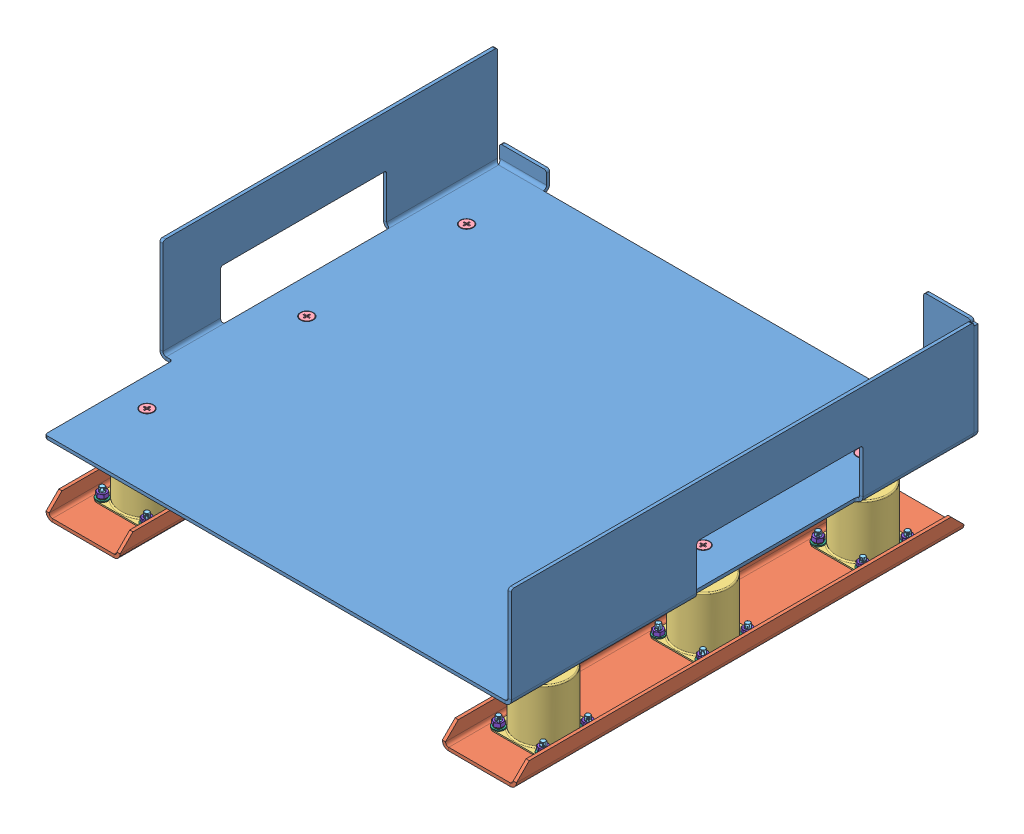
SolidWorks assembly Сборка, configuration По умолчанию. Lengths in mm.
Overall size (375.45 141.9 365.44).
111 component instances, 8 part files, 203 mates.
Components (placement in the parent):
- 1_Полка-1: 1_Полка [По умолчанию<Как обработанный>] at (-182.6691 43.1061 558.1681) size (375.45 80.44 365.44)
- 2_Основание-1: 2_Основание [По умолчанию] at (-150.1691 -18.3939 375.6681) x (0 0 -1) z (1 0 0) size (350 15 58)
- 2_Основание-2: 2_Основание [По умолчанию] at (159.8309 -18.3939 375.6681) x (0 0 1) z (-1 0 0) size (350 15 58)
- 8_Амортизатор-1: 8_Амортизатор [По умолчанию] at (-150.1691 -17.3939 500.6681) size (44 59 44)
- 8_Амортизатор-2: 8_Амортизатор [По умолчанию] at (-150.1691 -17.3939 375.6681) size (44 59 44)
- 8_Амортизатор-3: 8_Амортизатор [По умолчанию] at (159.8309 -17.3939 375.6681) size (44 59 44)
- 8_Амортизатор-4: 8_Амортизатор [По умолчанию] at (159.8309 -17.3939 250.6681) size (44 59 44)
- 8_Амортизатор-5: 8_Амортизатор [По умолчанию] at (159.8309 -17.3939 500.6681) size (44 59 44)
- 8_Амортизатор-6: 8_Амортизатор [По умолчанию] at (-150.1691 -17.3939 250.6681) size (44 59 44)
- 7_Винт_М5-1: 7_Винт_М5 [По умолчанию] at (159.8309 31.2061 250.6681) size (9.3 12.3 9.3)
- 7_Винт_М5-2: 7_Винт_М5 [По умолчанию] at (159.8309 31.2061 500.6681) size (9.3 12.3 9.3)
- 7_Винт_М5-3: 7_Винт_М5 [По умолчанию] at (159.8309 31.2061 375.6681) size (9.3 12.3 9.3)
- 7_Винт_М5-4: 7_Винт_М5 [По умолчанию] at (-150.1691 31.2061 500.6681) size (9.3 12.3 9.3)
- 7_Винт_М5-5: 7_Винт_М5 [По умолчанию] at (-150.1691 31.2061 375.6681) size (9.3 12.3 9.3)
- 7_Винт_М5-6: 7_Винт_М5 [По умолчанию] at (-150.1691 31.2061 250.6681) size (9.3 12.3 9.3)
- 6_Винт_М4-1: 6_Винт_М4 [По умолчанию] at (-132.6691 -9.2939 358.1681) x (1 0 0) z (0 0 -1) size (8.4 12.23 8.4)
- 6_Винт_М4-2: 6_Винт_М4 [По умолчанию] at (-132.6691 -9.2939 393.1681) x (1 0 0) z (0 0 -1) size (8.4 12.23 8.4)
- 6_Винт_М4-3: 6_Винт_М4 [По умолчанию] at (-132.6691 -9.2939 268.1681) x (1 0 0) z (0 0 -1) size (8.4 12.23 8.4)
- 6_Винт_М4-4: 6_Винт_М4 [По умолчанию] at (-132.6691 -9.2939 233.1681) x (1 0 0) z (0 0 -1) size (8.4 12.23 8.4)
- 6_Винт_М4-5: 6_Винт_М4 [По умолчанию] at (-167.6691 -9.2939 268.1681) x (1 0 0) z (0 0 -1) size (8.4 12.23 8.4)
- 6_Винт_М4-6: 6_Винт_М4 [По умолчанию] at (-167.6691 -9.2939 233.1681) x (1 0 0) z (0 0 -1) size (8.4 12.23 8.4)
- 6_Винт_М4-7: 6_Винт_М4 [По умолчанию] at (-167.6691 -9.2939 358.1681) x (1 0 0) z (0 0 -1) size (8.4 12.23 8.4)
- 6_Винт_М4-8: 6_Винт_М4 [По умолчанию] at (-167.6691 -9.2939 393.1681) x (1 0 0) z (0 0 -1) size (8.4 12.23 8.4)
- 6_Винт_М4-9: 6_Винт_М4 [По умолчанию] at (-132.6691 -9.2939 483.1681) x (1 0 0) z (0 0 -1) size (8.4 12.23 8.4)
- 6_Винт_М4-10: 6_Винт_М4 [По умолчанию] at (-167.6691 -9.2939 483.1681) x (1 0 0) z (0 0 -1) size (8.4 12.23 8.4)
- 6_Винт_М4-11: 6_Винт_М4 [По умолчанию] at (-132.6691 -9.2939 518.1681) x (1 0 0) z (0 0 -1) size (8.4 12.23 8.4)
- 6_Винт_М4-12: 6_Винт_М4 [По умолчанию] at (-167.6691 -9.2939 518.1681) x (1 0 0) z (0 0 -1) size (8.4 12.23 8.4)
- 6_Винт_М4-13: 6_Винт_М4 [По умолчанию] at (142.3309 -9.2939 393.1681) x (1 0 0) z (0 0 -1) size (8.4 12.23 8.4)
- 6_Винт_М4-14: 6_Винт_М4 [По умолчанию] at (177.3309 -9.2939 393.1681) x (1 0 0) z (0 0 -1) size (8.4 12.23 8.4)
- 6_Винт_М4-15: 6_Винт_М4 [По умолчанию] at (142.3309 -9.2939 358.1681) x (1 0 0) z (0 0 -1) size (8.4 12.23 8.4)
- 6_Винт_М4-16: 6_Винт_М4 [По умолчанию] at (177.3309 -9.2939 358.1681) x (1 0 0) z (0 0 -1) size (8.4 12.23 8.4)
- 6_Винт_М4-17: 6_Винт_М4 [По умолчанию] at (142.3309 -9.2939 268.1681) x (1 0 0) z (0 0 -1) size (8.4 12.23 8.4)
- 6_Винт_М4-18: 6_Винт_М4 [По умолчанию] at (177.3309 -9.2939 233.1681) x (1 0 0) z (0 0 -1) size (8.4 12.23 8.4)
- 6_Винт_М4-19: 6_Винт_М4 [По умолчанию] at (142.3309 -9.2939 233.1681) x (1 0 0) z (0 0 -1) size (8.4 12.23 8.4)
- 6_Винт_М4-20: 6_Винт_М4 [По умолчанию] at (177.3309 -9.2939 268.1681) x (1 0 0) z (0 0 -1) size (8.4 12.23 8.4)
- 6_Винт_М4-21: 6_Винт_М4 [По умолчанию] at (142.3309 -9.2939 483.1681) x (1 0 0) z (0 0 -1) size (8.4 12.23 8.4)
- 6_Винт_М4-22: 6_Винт_М4 [По умолчанию] at (142.3309 -9.2939 518.1681) x (1 0 0) z (0 0 -1) size (8.4 12.23 8.4)
- 6_Винт_М4-23: 6_Винт_М4 [По умолчанию] at (177.3309 -9.2939 518.1681) x (1 0 0) z (0 0 -1) size (8.4 12.23 8.4)
- 6_Винт_М4-24: 6_Винт_М4 [По умолчанию] at (177.3309 -9.2939 483.1681) x (1 0 0) z (0 0 -1) size (8.4 12.23 8.4)
- 5_Шайба_А4-1: 5_Шайба_А4 [По умолчанию] at (-167.6691 -17.3939 483.1681) size (9 0.8 9)
- 5_Шайба_А4-2: 5_Шайба_А4 [По умолчанию] at (-167.6691 -17.3939 518.1681) size (9 0.8 9)
- 5_Шайба_А4-3: 5_Шайба_А4 [По умолчанию] at (-132.6691 -17.3939 483.1681) size (9 0.8 9)
- 5_Шайба_А4-4: 5_Шайба_А4 [По умолчанию] at (-132.6691 -17.3939 518.1681) size (9 0.8 9)
- 5_Шайба_А4-5: 5_Шайба_А4 [По умолчанию] at (-132.6691 -17.3939 358.1681) size (9 0.8 9)
- 5_Шайба_А4-6: 5_Шайба_А4 [По умолчанию] at (-167.6691 -17.3939 358.1681) x (0.667265 0 0.74482) z (-0.74482 0 0.667265) size (9 0.8 9)
- 5_Шайба_А4-7: 5_Шайба_А4 [По умолчанию] at (-132.6691 -17.3939 393.1681) size (9 0.8 9)
- 5_Шайба_А4-8: 5_Шайба_А4 [По умолчанию] at (-167.6691 -17.3939 393.1681) x (0.975059 0 0.221947) z (-0.221947 0 0.975059) size (9 0.8 9)
- 5_Шайба_А4-9: 5_Шайба_А4 [По умолчанию] at (-167.6691 -17.3939 268.1681) size (9 0.8 9)
- 5_Шайба_А4-10: 5_Шайба_А4 [По умолчанию] at (-132.6691 -17.3939 268.1681) size (9 0.8 9)
- 5_Шайба_А4-11: 5_Шайба_А4 [По умолчанию] at (-167.6691 -17.3939 233.1681) size (9 0.8 9)
- 5_Шайба_А4-12: 5_Шайба_А4 [По умолчанию] at (-132.6691 -17.3939 233.1681) size (9 0.8 9)
- 5_Шайба_А4-13: 5_Шайба_А4 [По умолчанию] at (142.3309 -17.3939 518.1681) size (9 0.8 9)
- 5_Шайба_А4-14: 5_Шайба_А4 [По умолчанию] at (142.3309 -17.3939 483.1681) size (9 0.8 9)
- 5_Шайба_А4-15: 5_Шайба_А4 [По умолчанию] at (177.3309 -17.3939 483.1681) size (9 0.8 9)
- 5_Шайба_А4-16: 5_Шайба_А4 [По умолчанию] at (177.3309 -17.3939 518.1681) size (9 0.8 9)
- 5_Шайба_А4-17: 5_Шайба_А4 [По умолчанию] at (142.3309 -17.3939 358.1681) size (9 0.8 9)
- 5_Шайба_А4-18: 5_Шайба_А4 [По умолчанию] at (177.3309 -17.3939 393.1681) size (9 0.8 9)
- 5_Шайба_А4-19: 5_Шайба_А4 [По умолчанию] at (142.3309 -17.3939 393.1681) size (9 0.8 9)
- 5_Шайба_А4-20: 5_Шайба_А4 [По умолчанию] at (177.3309 -17.3939 358.1681) size (9 0.8 9)
- 5_Шайба_А4-21: 5_Шайба_А4 [По умолчанию] at (142.3309 -17.3939 268.1681) size (9 0.8 9)
- 5_Шайба_А4-22: 5_Шайба_А4 [По умолчанию] at (142.3309 -17.3939 233.1681) size (9 0.8 9)
- 5_Шайба_А4-23: 5_Шайба_А4 [По умолчанию] at (177.3309 -17.3939 233.1681) size (9 0.8 9)
- 5_Шайба_А4-24: 5_Шайба_А4 [По умолчанию] at (177.3309 -17.3939 268.1681) size (9 0.8 9)
- 4_Шайба-1: 4_Шайба [По умолчанию] at (-132.6691 -16.5939 518.1681) x (-0.950092 0 -0.311971) z (0.311971 0 -0.950092) size (6.5 0.8 6.5)
- 4_Шайба-2: 4_Шайба [По умолчанию] at (-167.6691 -16.5939 518.1681) x (-0.964104 0 -0.265525) z (0.265525 0 -0.964104) size (6.5 0.8 6.5)
- 4_Шайба-3: 4_Шайба [По умолчанию] at (-167.6691 -16.5939 483.1681) x (-0.900004 0 -0.435881) z (0.435881 0 -0.900004) size (6.5 0.8 6.5)
- 4_Шайба-4: 4_Шайба [По умолчанию] at (-132.6691 -16.5939 483.1681) x (0.833959 0 0.551827) z (-0.551827 0 0.833959) size (6.5 0.8 6.5)
- 4_Шайба-5: 4_Шайба [По умолчанию] at (-167.6691 -16.5939 358.1681) x (0.466083 0 -0.884741) z (0.884741 0 0.466083) size (6.5 0.8 6.5)
- 4_Шайба-6: 4_Шайба [По умолчанию] at (-132.6691 -16.5939 358.1681) x (0.892908 0 0.450239) z (-0.450239 0 0.892908) size (6.5 0.8 6.5)
- 4_Шайба-7: 4_Шайба [По умолчанию] at (-167.6691 -16.5939 393.1681) x (-0.311106 0 -0.950375) z (0.950375 0 -0.311106) size (6.5 0.8 6.5)
- 4_Шайба-8: 4_Шайба [По умолчанию] at (-132.6691 -16.5939 393.1681) size (6.5 0.8 6.5)
- 4_Шайба-13: 4_Шайба [По умолчанию] at (-132.6691 -16.5939 233.1681) size (6.5 0.8 6.5)
- 4_Шайба-14: 4_Шайба [По умолчанию] at (-167.6691 -16.5939 268.1681) size (6.5 0.8 6.5)
- 4_Шайба-15: 4_Шайба [По умолчанию] at (-132.6691 -16.5939 268.1681) x (0.985052 0 -0.172259) z (0.172259 0 0.985052) size (6.5 0.8 6.5)
- 4_Шайба-16: 4_Шайба [По умолчанию] at (-167.6691 -16.5939 233.1681) size (6.5 0.8 6.5)
- 4_Шайба-17: 4_Шайба [По умолчанию] at (177.3309 -16.5939 518.1681) x (-0.952485 0 -0.304585) z (0.304585 0 -0.952485) size (6.5 0.8 6.5)
- 4_Шайба-19: 4_Шайба [По умолчанию] at (142.3309 -16.5939 518.1681) x (-0.742093 0 -0.670297) z (0.670297 0 -0.742093) size (6.5 0.8 6.5)
- 4_Шайба-20: 4_Шайба [По умолчанию] at (142.3309 -16.5939 483.1681) x (0.157887 0 -0.987457) z (0.987457 0 0.157887) size (6.5 0.8 6.5)
- 4_Шайба-21: 4_Шайба [По умолчанию] at (177.3309 -16.5939 483.1681) x (0.73951 0 0.673145) z (-0.673145 0 0.73951) size (6.5 0.8 6.5)
- 4_Шайба-22: 4_Шайба [По умолчанию] at (177.3309 -16.5939 233.1681) x (0.8131 0 0.582125) z (-0.582125 0 0.8131) size (6.5 0.8 6.5)
- 4_Шайба-23: 4_Шайба [По умолчанию] at (142.3309 -16.5939 233.1681) size (6.5 0.8 6.5)
- 4_Шайба-24: 4_Шайба [По умолчанию] at (142.3309 -16.5939 268.1681) size (6.5 0.8 6.5)
- 4_Шайба-25: 4_Шайба [По умолчанию] at (177.3309 -16.5939 268.1681) x (-0.997954 0 -0.063934) z (0.063934 0 -0.997954) size (6.5 0.8 6.5)
- 4_Шайба-26: 4_Шайба [По умолчанию] at (142.3309 -16.5939 358.1681) size (6.5 0.8 6.5)
- 4_Шайба-27: 4_Шайба [По умолчанию] at (142.3309 -16.5939 393.1681) size (6.5 0.8 6.5)
- 4_Шайба-28: 4_Шайба [По умолчанию] at (177.3309 -16.5939 358.1681) x (0.299403 0 0.954127) z (-0.954127 0 0.299403) size (6.5 0.8 6.5)
- 4_Шайба-29: 4_Шайба [По умолчанию] at (177.3309 -16.5939 393.1681) size (6.5 0.8 6.5)
- 3_Гайка-1: 3_Гайка [По умолчанию] at (142.3309 -15.7939 483.1681) size (6.78 3.14 7.83)
- 3_Гайка-2: 3_Гайка [По умолчанию] at (177.3309 -15.7939 483.1681) size (6.78 3.14 7.83)
- 3_Гайка-3: 3_Гайка [По умолчанию] at (177.3309 -15.7939 518.1681) size (6.78 3.14 7.83)
- 3_Гайка-4: 3_Гайка [По умолчанию] at (142.3309 -15.7939 518.1681) size (6.78 3.14 7.83)
- 3_Гайка-5: 3_Гайка [По умолчанию] at (142.3309 -16.5939 393.1681) size (6.78 3.14 7.83)
- 3_Гайка-6: 3_Гайка [По умолчанию] at (177.3309 -15.7939 393.1681) size (6.78 3.14 7.83)
- 3_Гайка-7: 3_Гайка [По умолчанию] at (177.3309 -15.7939 358.1681) size (6.78 3.14 7.83)
- 3_Гайка-8: 3_Гайка [По умолчанию] at (142.3309 -15.7939 358.1681) size (6.78 3.14 7.83)
- 3_Гайка-9: 3_Гайка [По умолчанию] at (177.3309 -15.7939 268.1681) size (6.78 3.14 7.83)
- 3_Гайка-10: 3_Гайка [По умолчанию] at (142.3309 -15.7939 233.1681) size (6.78 3.14 7.83)
- 3_Гайка-11: 3_Гайка [По умолчанию] at (177.3309 -15.7939 233.1681) size (6.78 3.14 7.83)
- 3_Гайка-12: 3_Гайка [По умолчанию] at (142.3309 -15.7939 268.1681) x (0.892685 0 0.450682) z (-0.450682 0 0.892685) size (6.78 3.14 7.83)
- 3_Гайка-13: 3_Гайка [По умолчанию] at (-167.6691 -15.7939 268.1681) size (6.78 3.14 7.83)
- 3_Гайка-14: 3_Гайка [По умолчанию] at (-167.6691 -15.7939 233.1681) size (6.78 3.14 7.83)
- 3_Гайка-15: 3_Гайка [По умолчанию] at (-132.6691 -15.7939 233.1681) x (0.109606 0 -0.993975) z (0.993975 0 0.109606) size (6.78 3.14 7.83)
- 3_Гайка-16: 3_Гайка [По умолчанию] at (-132.6691 -15.7939 268.1681) size (6.78 3.14 7.83)
- 3_Гайка-17: 3_Гайка [По умолчанию] at (-167.6691 -15.7939 358.1681) size (6.78 3.14 7.83)
- 3_Гайка-18: 3_Гайка [По умолчанию] at (-132.6691 -15.7939 393.1681) size (6.78 3.14 7.83)
- 3_Гайка-19: 3_Гайка [По умолчанию] at (-167.6691 -15.7939 393.1681) size (6.78 3.14 7.83)
- 3_Гайка-20: 3_Гайка [По умолчанию] at (-132.6691 -15.7939 358.1681) size (6.78 3.14 7.83)
- 3_Гайка-21: 3_Гайка [По умолчанию] at (-132.6691 -15.7939 483.1681) size (6.78 3.14 7.83)
- 3_Гайка-22: 3_Гайка [По умолчанию] at (-167.6691 -15.7939 518.1681) size (6.78 3.14 7.83)
- 3_Гайка-23: 3_Гайка [По умолчанию] at (-132.6691 -15.7939 518.1681) size (6.78 3.14 7.83)
- 3_Гайка-24: 3_Гайка [По умолчанию] at (-167.6691 -15.7939 483.1681) size (6.78 3.14 7.83)
Mates (geometry in assembly coordinates):
- Концентричный1: concentric aligned: circle of 1_Полка-1; circle of 8_Амортизатор-6
- Совпадение2: coincident anti-aligned: plane of 1_Полка-1 through (-182.6691 40.6061 558.1681) normal (0 -1 0); plane of 8_Амортизатор-6 through (-150.1691 40.6061 250.6681) normal (0 1 0)
- Совпадение3: coincident aligned: cone of 1_Полка-1 through (-150.1691 40.7561 250.6681) axis (0 -1 0); cone of 7_Винт_М5-6 through (-150.1691 42.6561 250.6681) axis (0 -1 0)
- Концентричный2: concentric aligned: circle of 1_Полка-1; circle of 8_Амортизатор-2
- Совпадение4: coincident anti-aligned: plane of 1_Полка-1 through (-182.6691 40.6061 558.1681) normal (0 -1 0); plane of 8_Амортизатор-2 through (-150.1691 40.6061 375.6681) normal (0 1 0)
- Концентричный3: concentric aligned: circle of 1_Полка-1; circle of 8_Амортизатор-1
- Совпадение5: coincident anti-aligned: plane of 1_Полка-1 through (-182.6691 40.6061 558.1681) normal (0 -1 0); plane of 8_Амортизатор-1 through (-150.1691 40.6061 500.6681) normal (0 1 0)
- Концентричный4: concentric aligned: circle of 1_Полка-1; circle of 8_Амортизатор-4
- Совпадение6: coincident anti-aligned: plane of 1_Полка-1 through (-182.6691 40.6061 558.1681) normal (0 -1 0); plane of 8_Амортизатор-4 through (159.8309 40.6061 250.6681) normal (0 1 0)
- Концентричный5: concentric aligned: circle of 1_Полка-1; circle of 8_Амортизатор-3
- Совпадение7: coincident anti-aligned: plane of 1_Полка-1 through (-182.6691 40.6061 558.1681) normal (0 -1 0); plane of 8_Амортизатор-3 through (159.8309 40.6061 375.6681) normal (0 1 0)
- Концентричный6: concentric aligned: circle of 1_Полка-1; circle of 8_Амортизатор-5
- Совпадение8: coincident anti-aligned: plane of 1_Полка-1 through (-182.6691 40.6061 558.1681) normal (0 -1 0); plane of 8_Амортизатор-5 through (159.8309 40.6061 500.6681) normal (0 1 0)
- Совпадение9: coincident aligned: cone of 1_Полка-1 through (-150.1691 40.7561 375.6681) axis (0 -1 0); cone of 7_Винт_М5-5 through (-150.1691 42.6561 375.6681) axis (0 -1 0)
- Совпадение10: coincident aligned: cone of 1_Полка-1 through (-150.1691 40.7561 500.6681) axis (0 -1 0); cone of 7_Винт_М5-4 through (-150.1691 42.6561 500.6681) axis (0 -1 0)
- Совпадение11: coincident aligned: cone of 1_Полка-1 through (159.8309 40.7561 500.6681) axis (0 -1 0); cone of 7_Винт_М5-2 through (159.8309 42.6561 500.6681) axis (0 -1 0)
- Совпадение12: coincident aligned: cone of 1_Полка-1 through (159.8309 40.7561 375.6681) axis (0 -1 0); cone of 7_Винт_М5-3 through (159.8309 42.6561 375.6681) axis (0 -1 0)
- Совпадение14: coincident aligned: cone of 1_Полка-1 through (159.8309 40.7561 250.6681) axis (0 -1 0); cone of 7_Винт_М5-1 through (159.8309 42.6561 250.6681) axis (0 -1 0)
- Концентричный11: concentric aligned: circle of 2_Основание-1; circle of 8_Амортизатор-6
- Концентричный12: concentric aligned: circle of 2_Основание-1; circle of 8_Амортизатор-6
- Концентричный13: concentric aligned: circle of 2_Основание-1; circle of 8_Амортизатор-2
- Концентричный14: concentric anti-aligned: cylinder of 2_Основание-1; cylinder of 8_Амортизатор-2 through (-132.6691 24.8061 393.1681) axis (0 -1 0) radius 2
- Концентричный15: concentric anti-aligned: circle of 2_Основание-1; cylinder of 8_Амортизатор-1 through (-167.6691 24.8061 483.1681) axis (0 -1 0) radius 2
- Концентричный16: concentric aligned: circle of 2_Основание-1; circle of 8_Амортизатор-1
- Совпадение15: coincident anti-aligned: plane of 2_Основание-1 through (-150.1691 -18.3939 375.6681) normal (0 1 0); plane of 8_Амортизатор-1 through (-150.1691 -18.3939 500.6681) normal (0 -1 0)
- Совпадение16: coincident aligned: cone of 2_Основание-1 through (-167.6691 -20.8939 518.1681) axis (0 1 0); cone of 6_Винт_М4-12 through (-167.6691 -20.7939 518.1681) axis (0 1 0)
- Совпадение17: coincident aligned: cone of 2_Основание-1 through (-132.6691 -20.8939 518.1681) axis (0 1 0); cone of 6_Винт_М4-11 through (-132.6691 -20.7939 518.1681) axis (0 1 0)
- Совпадение18: coincident anti-aligned: cone of 2_Основание-1 through (-167.6691 -20.8939 483.1681) axis (0 1 0); circle of 6_Винт_М4-10
- Совпадение19: coincident anti-aligned: cone of 2_Основание-1 through (-132.6691 -20.8939 483.1681) axis (0 1 0); circle of 6_Винт_М4-9
- Совпадение20: coincident aligned: cone of 2_Основание-1 through (-167.6691 -20.8939 393.1681) axis (0 1 0); cone of 6_Винт_М4-8 through (-167.6691 -20.7939 393.1681) axis (0 1 0)
- Совпадение21: coincident aligned: cone of 2_Основание-1 through (-132.6691 -20.8939 358.1681) axis (0 1 0); cone of 6_Винт_М4-1 through (-132.6691 -20.7939 358.1681) axis (0 1 0)
- Совпадение22: coincident aligned: cone of 2_Основание-1 through (-167.6691 -20.8939 358.1681) axis (0 1 0); cone of 6_Винт_М4-7 through (-167.6691 -20.7939 358.1681) axis (0 1 0)
- Совпадение23: coincident aligned: cone of 2_Основание-1 through (-132.6691 -20.8939 393.1681) axis (0 1 0); cone of 6_Винт_М4-2 through (-132.6691 -20.7939 393.1681) axis (0 1 0)
- Совпадение24: coincident aligned: cone of 2_Основание-1 through (-167.6691 -20.8939 268.1681) axis (0 1 0); cone of 6_Винт_М4-5 through (-167.6691 -20.7939 268.1681) axis (0 1 0)
- Совпадение25: coincident aligned: cone of 2_Основание-1 through (-167.6691 -20.8939 233.1681) axis (0 1 0); cone of 6_Винт_М4-6 through (-167.6691 -20.7939 233.1681) axis (0 1 0)
- Совпадение26: coincident aligned: cone of 2_Основание-1 through (-132.6691 -20.8939 233.1681) axis (0 1 0); cone of 6_Винт_М4-4 through (-132.6691 -20.7939 233.1681) axis (0 1 0)
- Совпадение27: coincident aligned: cone of 2_Основание-1 through (-132.6691 -20.8939 268.1681) axis (0 1 0); cone of 6_Винт_М4-3 through (-132.6691 -20.7939 268.1681) axis (0 1 0)
- Концентричный17: concentric anti-aligned: circle of 2_Основание-2; cylinder of 8_Амортизатор-5 through (142.3309 24.8061 483.1681) axis (0 -1 0) radius 2
- Концентричный18: concentric anti-aligned: circle of 2_Основание-2; cylinder of 8_Амортизатор-5 through (177.3309 24.8061 518.1681) axis (0 -1 0) radius 2
- Концентричный19: concentric anti-aligned: circle of 2_Основание-2; cylinder of 8_Амортизатор-3 through (142.3309 24.8061 393.1681) axis (0 -1 0) radius 2
- Концентричный20: concentric aligned: circle of 2_Основание-2; circle of 8_Амортизатор-3
- Концентричный21: concentric anti-aligned: circle of 2_Основание-2; cylinder of 8_Амортизатор-4 through (142.3309 24.8061 268.1681) axis (0 -1 0) radius 2
- Концентричный22: concentric anti-aligned: circle of 2_Основание-2; cylinder of 8_Амортизатор-4 through (177.3309 24.8061 233.1681) axis (0 -1 0) radius 2
- Совпадение28: coincident anti-aligned: plane of 2_Основание-2 through (159.8309 -18.3939 375.6681) normal (0 1 0); plane of 8_Амортизатор-5 through (159.8309 -18.3939 500.6681) normal (0 -1 0)
- Совпадение29: coincident aligned: cone of 2_Основание-2 through (142.3309 -20.8939 518.1681) axis (0 1 0); cone of 6_Винт_М4-22 through (142.3309 -20.7939 518.1681) axis (0 1 0)
- Совпадение30: coincident aligned: cone of 2_Основание-2 through (177.3309 -20.8939 518.1681) axis (0 1 0); cone of 6_Винт_М4-23 through (177.3309 -20.7939 518.1681) axis (0 1 0)
- Совпадение31: coincident aligned: cone of 2_Основание-2 through (142.3309 -20.8939 483.1681) axis (0 1 0); cone of 6_Винт_М4-21 through (142.3309 -20.7939 483.1681) axis (0 1 0)
- Совпадение32: coincident aligned: cone of 2_Основание-2 through (177.3309 -20.8939 483.1681) axis (0 1 0); cone of 6_Винт_М4-24 through (177.3309 -20.7939 483.1681) axis (0 1 0)
- Совпадение33: coincident aligned: cone of 2_Основание-2 through (142.3309 -20.8939 393.1681) axis (0 1 0); cone of 6_Винт_М4-13 through (142.3309 -20.7939 393.1681) axis (0 1 0)
- Совпадение34: coincident aligned: cone of 2_Основание-2 through (177.3309 -20.8939 393.1681) axis (0 1 0); cone of 6_Винт_М4-14 through (177.3309 -20.7939 393.1681) axis (0 1 0)
- Совпадение35: coincident aligned: cone of 2_Основание-2 through (142.3309 -20.8939 358.1681) axis (0 1 0); cone of 6_Винт_М4-15 through (142.3309 -20.7939 358.1681) axis (0 1 0)
- Совпадение36: coincident aligned: cone of 2_Основание-2 through (177.3309 -20.8939 358.1681) axis (0 1 0); cone of 6_Винт_М4-16 through (177.3309 -20.7939 358.1681) axis (0 1 0)
- Совпадение37: coincident aligned: cone of 2_Основание-2 through (142.3309 -20.8939 268.1681) axis (0 1 0); cone of 6_Винт_М4-17 through (142.3309 -20.7939 268.1681) axis (0 1 0)
- Совпадение38: coincident aligned: cone of 2_Основание-2 through (177.3309 -20.8939 233.1681) axis (0 1 0); cone of 6_Винт_М4-18 through (177.3309 -20.7939 233.1681) axis (0 1 0)
- Совпадение39: coincident aligned: cone of 2_Основание-2 through (177.3309 -20.8939 268.1681) axis (0 1 0); cone of 6_Винт_М4-20 through (177.3309 -20.7939 268.1681) axis (0 1 0)
- Совпадение40: coincident aligned: cone of 2_Основание-2 through (142.3309 -20.8939 233.1681) axis (0 1 0); cone of 6_Винт_М4-19 through (142.3309 -20.7939 233.1681) axis (0 1 0)
- Совпадение43: coincident anti-aligned: plane of 8_Амортизатор-1 through (-150.1691 -17.3939 500.6681) normal (0 1 0); plane of 5_Шайба_А4-2 through (-167.6691 -17.3939 518.1681) normal (0 -1 0)
- Концентричный24: concentric aligned: circle of 8_Амортизатор-1; circle of 5_Шайба_А4-2
- Совпадение44: coincident anti-aligned: plane of 8_Амортизатор-1 through (-150.1691 -17.3939 500.6681) normal (0 1 0); plane of 5_Шайба_А4-4 through (-132.6691 -17.3939 518.1681) normal (0 -1 0)
- Концентричный25: concentric aligned: circle of 8_Амортизатор-1; circle of 5_Шайба_А4-4
- Совпадение45: coincident anti-aligned: plane of 8_Амортизатор-1 through (-150.1691 -17.3939 500.6681) normal (0 1 0); plane of 5_Шайба_А4-1 through (-167.6691 -17.3939 483.1681) normal (0 -1 0)
- Концентричный26: concentric aligned: circle of 8_Амортизатор-1; circle of 5_Шайба_А4-1
- Совпадение46: coincident aligned: plane of 8_Амортизатор-1 through (-150.1691 -17.3939 500.6681) normal (0 1 0); circle of 5_Шайба_А4-3
- Концентричный27: concentric aligned: circle of 8_Амортизатор-1; circle of 5_Шайба_А4-3
- Концентричный28: concentric aligned: circle of 8_Амортизатор-2; circle of 5_Шайба_А4-7
- Совпадение47: coincident anti-aligned: plane of 8_Амортизатор-2 through (-150.1691 -17.3939 375.6681) normal (0 1 0); plane of 5_Шайба_А4-7 through (-132.6691 -17.3939 393.1681) normal (0 -1 0)
- Концентричный29: concentric aligned: circle of 8_Амортизатор-2; circle of 5_Шайба_А4-8
- Совпадение49: coincident anti-aligned: plane of 8_Амортизатор-2 through (-150.1691 -17.3939 375.6681) normal (0 1 0); plane of 5_Шайба_А4-8 through (-167.6691 -17.3939 393.1681) normal (0 -1 0)
- Концентричный30: concentric aligned: circle of 8_Амортизатор-2; circle of 5_Шайба_А4-6
- Совпадение51: coincident anti-aligned: plane of 8_Амортизатор-2 through (-150.1691 -17.3939 375.6681) normal (0 1 0); plane of 5_Шайба_А4-6 through (-167.6691 -17.3939 358.1681) normal (0 -1 0)
- Концентричный31: concentric aligned: circle of 8_Амортизатор-2; circle of 5_Шайба_А4-5
- Совпадение54: coincident anti-aligned: plane of 8_Амортизатор-2 through (-150.1691 -17.3939 375.6681) normal (0 1 0); plane of 5_Шайба_А4-5 through (-132.6691 -17.3939 358.1681) normal (0 -1 0)
- Концентричный32: concentric aligned: circle of 8_Амортизатор-6; circle of 5_Шайба_А4-9
- Совпадение55: coincident anti-aligned: plane of 8_Амортизатор-6 through (-150.1691 -17.3939 250.6681) normal (0 1 0); plane of 5_Шайба_А4-9 through (-167.6691 -17.3939 268.1681) normal (0 -1 0)
- Совпадение56: coincident anti-aligned: plane of 8_Амортизатор-6 through (-150.1691 -17.3939 250.6681) normal (0 1 0); plane of 5_Шайба_А4-11 through (-167.6691 -17.3939 233.1681) normal (0 -1 0)
- Совпадение57: coincident anti-aligned: plane of 8_Амортизатор-6 through (-150.1691 -17.3939 250.6681) normal (0 1 0); plane of 5_Шайба_А4-10 through (-132.6691 -17.3939 268.1681) normal (0 -1 0)
- Совпадение58: coincident aligned: plane of 8_Амортизатор-6 through (-150.1691 -17.3939 250.6681) normal (0 1 0); circle of 5_Шайба_А4-12
- Концентричный33: concentric aligned: circle of 8_Амортизатор-6; circle of 5_Шайба_А4-12
- Концентричный34: concentric aligned: circle of 8_Амортизатор-6; circle of 5_Шайба_А4-11
- Концентричный35: concentric aligned: circle of 8_Амортизатор-6; circle of 5_Шайба_А4-10
- Совпадение59: coincident aligned: plane of 5_Шайба_А4-23 through (177.3309 -17.3939 233.1681) normal (0 -1 0); plane of 5_Шайба_А4-24 through (177.3309 -17.3939 268.1681) normal (0 -1 0)
- Совпадение60: coincident aligned: plane of 5_Шайба_А4-21 through (142.3309 -17.3939 268.1681) normal (0 -1 0); plane of 5_Шайба_А4-23 through (177.3309 -17.3939 233.1681) normal (0 -1 0)
- Совпадение61: coincident aligned: plane of 5_Шайба_А4-22 through (142.3309 -17.3939 233.1681) normal (0 -1 0); plane of 5_Шайба_А4-23 through (177.3309 -17.3939 233.1681) normal (0 -1 0)
- Совпадение62: coincident anti-aligned: plane of 8_Амортизатор-4 through (159.8309 -17.3939 250.6681) normal (0 1 0); plane of 5_Шайба_А4-23 through (177.3309 -17.3939 233.1681) normal (0 -1 0)
- Совпадение63: coincident anti-aligned: plane of 8_Амортизатор-4 through (159.8309 -17.3939 250.6681) normal (0 1 0); plane of 5_Шайба_А4-22 through (142.3309 -17.3939 233.1681) normal (0 -1 0)
- Совпадение64: coincident anti-aligned: plane of 8_Амортизатор-4 through (159.8309 -17.3939 250.6681) normal (0 1 0); plane of 5_Шайба_А4-21 through (142.3309 -17.3939 268.1681) normal (0 -1 0)
- Совпадение65: coincident anti-aligned: plane of 8_Амортизатор-4 through (159.8309 -17.3939 250.6681) normal (0 1 0); plane of 5_Шайба_А4-24 through (177.3309 -17.3939 268.1681) normal (0 -1 0)
- Концентричный36: concentric aligned: circle of 8_Амортизатор-4; circle of 5_Шайба_А4-24
- Концентричный37: concentric aligned: circle of 8_Амортизатор-4; circle of 5_Шайба_А4-21
- Концентричный38: concentric aligned: circle of 8_Амортизатор-4; circle of 5_Шайба_А4-23
- Концентричный39: concentric aligned: circle of 8_Амортизатор-4; circle of 5_Шайба_А4-22
- Совпадение66: coincident anti-aligned: plane of 8_Амортизатор-3 through (159.8309 -17.3939 375.6681) normal (0 1 0); plane of 5_Шайба_А4-18 through (177.3309 -17.3939 393.1681) normal (0 -1 0)
- Концентричный40: concentric aligned: circle of 8_Амортизатор-3; circle of 5_Шайба_А4-18
- Совпадение67: coincident anti-aligned: plane of 8_Амортизатор-3 through (159.8309 -17.3939 375.6681) normal (0 1 0); plane of 5_Шайба_А4-20 through (177.3309 -17.3939 358.1681) normal (0 -1 0)
- Концентричный41: concentric aligned: circle of 8_Амортизатор-3; circle of 5_Шайба_А4-20
- Совпадение68: coincident anti-aligned: plane of 8_Амортизатор-3 through (159.8309 -17.3939 375.6681) normal (0 1 0); plane of 5_Шайба_А4-17 through (142.3309 -17.3939 358.1681) normal (0 -1 0)
- Концентричный42: concentric aligned: circle of 8_Амортизатор-3; circle of 5_Шайба_А4-17
- Совпадение69: coincident anti-aligned: plane of 8_Амортизатор-3 through (159.8309 -17.3939 375.6681) normal (0 1 0); plane of 5_Шайба_А4-19 through (142.3309 -17.3939 393.1681) normal (0 -1 0)
- Концентричный43: concentric aligned: circle of 8_Амортизатор-3; circle of 5_Шайба_А4-19
- Совпадение70: coincident anti-aligned: plane of 8_Амортизатор-5 through (159.8309 -17.3939 500.6681) normal (0 1 0); plane of 5_Шайба_А4-15 through (177.3309 -17.3939 483.1681) normal (0 -1 0)
- Концентричный44: concentric aligned: circle of 8_Амортизатор-5; circle of 5_Шайба_А4-15
- Совпадение71: coincident anti-aligned: plane of 8_Амортизатор-5 through (159.8309 -17.3939 500.6681) normal (0 1 0); plane of 5_Шайба_А4-14 through (142.3309 -17.3939 483.1681) normal (0 -1 0)
- Концентричный45: concentric anti-aligned: circle of 8_Амортизатор-5; cylinder of 5_Шайба_А4-14 through (142.3309 -16.5939 483.1681) axis (0 -1 0) radius 2.15
- Совпадение72: coincident anti-aligned: plane of 8_Амортизатор-5 through (159.8309 -17.3939 500.6681) normal (0 1 0); plane of 5_Шайба_А4-13 through (142.3309 -17.3939 518.1681) normal (0 -1 0)
- Концентричный46: concentric aligned: circle of 8_Амортизатор-5; circle of 5_Шайба_А4-13
- Совпадение73: coincident anti-aligned: plane of 8_Амортизатор-5 through (159.8309 -17.3939 500.6681) normal (0 1 0); plane of 5_Шайба_А4-16 through (177.3309 -17.3939 518.1681) normal (0 -1 0)
- Концентричный47: concentric aligned: circle of 8_Амортизатор-5; circle of 5_Шайба_А4-16
- Совпадение74: coincident anti-aligned: plane of 5_Шайба_А4-1 through (-167.6691 -16.5939 483.1681) normal (0 1 0); plane of 4_Шайба-3 through (-167.6691 -16.5939 483.1681) normal (0 -1 0)
- Концентричный48: concentric aligned: circle of 5_Шайба_А4-1; circle of 4_Шайба-3
- Совпадение75: coincident anti-aligned: plane of 5_Шайба_А4-2 through (-167.6691 -16.5939 518.1681) normal (0 1 0); plane of 4_Шайба-2 through (-167.6691 -16.5939 518.1681) normal (0 -1 0)
- Концентричный49: concentric aligned: circle of 5_Шайба_А4-2; circle of 4_Шайба-2
- Совпадение76: coincident anti-aligned: plane of 5_Шайба_А4-4 through (-132.6691 -16.5939 518.1681) normal (0 1 0); plane of 4_Шайба-1 through (-132.6691 -16.5939 518.1681) normal (0 -1 0)
- Концентричный50: concentric aligned: circle of 5_Шайба_А4-4; circle of 4_Шайба-1
- Совпадение77: coincident anti-aligned: plane of 5_Шайба_А4-3 through (-132.6691 -16.5939 483.1681) normal (0 1 0); plane of 4_Шайба-4 through (-132.6691 -16.5939 483.1681) normal (0 -1 0)
- Концентричный51: concentric aligned: circle of 5_Шайба_А4-3; circle of 4_Шайба-4
- Совпадение78: coincident anti-aligned: plane of 5_Шайба_А4-8 through (-167.6691 -16.5939 393.1681) normal (0 1 0); plane of 4_Шайба-7 through (-167.6691 -16.5939 393.1681) normal (0 -1 0)
- Концентричный52: concentric aligned: circle of 5_Шайба_А4-8; circle of 4_Шайба-7
- Совпадение79: coincident anti-aligned: plane of 5_Шайба_А4-6 through (-167.6691 -16.5939 358.1681) normal (0 1 0); plane of 4_Шайба-5 through (-167.6691 -16.5939 358.1681) normal (0 -1 0)
- Концентричный53: concentric aligned: circle of 5_Шайба_А4-6; circle of 4_Шайба-5
- Совпадение80: coincident aligned: plane of 5_Шайба_А4-7 through (-132.6691 -16.5939 393.1681) normal (0 1 0); circle of 4_Шайба-8
- Концентричный56: concentric aligned: circle of 5_Шайба_А4-7; circle of 4_Шайба-8
- Совпадение82: coincident anti-aligned: plane of 5_Шайба_А4-5 through (-132.6691 -16.5939 358.1681) normal (0 1 0); plane of 4_Шайба-6 through (-132.6691 -16.5939 358.1681) normal (0 -1 0)
- Концентричный57: concentric aligned: circle of 5_Шайба_А4-5; circle of 4_Шайба-6
- Совпадение83: coincident anti-aligned: plane of 5_Шайба_А4-12 through (-132.6691 -16.5939 233.1681) normal (0 1 0); plane of 4_Шайба-13 through (-132.6691 -16.5939 233.1681) normal (0 -1 0)
- Концентричный58: concentric aligned: circle of 5_Шайба_А4-12; circle of 4_Шайба-13
- Совпадение84: coincident anti-aligned: plane of 5_Шайба_А4-11 through (-167.6691 -16.5939 233.1681) normal (0 1 0); plane of 4_Шайба-16 through (-167.6691 -16.5939 233.1681) normal (0 -1 0)
- Концентричный59: concentric aligned: circle of 5_Шайба_А4-11; circle of 4_Шайба-16
- Совпадение85: coincident anti-aligned: plane of 5_Шайба_А4-9 through (-167.6691 -16.5939 268.1681) normal (0 1 0); plane of 4_Шайба-14 through (-167.6691 -16.5939 268.1681) normal (0 -1 0)
- Концентричный60: concentric aligned: circle of 5_Шайба_А4-9; circle of 4_Шайба-14
- Концентричный61: concentric aligned: circle of 5_Шайба_А4-10; circle of 4_Шайба-15
- Совпадение88: coincident aligned: plane of 5_Шайба_А4-10 through (-132.6691 -16.5939 268.1681) normal (0 1 0); circle of 4_Шайба-15
- Совпадение89: coincident anti-aligned: plane of 5_Шайба_А4-13 through (142.3309 -16.5939 518.1681) normal (0 1 0); plane of 4_Шайба-19 through (142.3309 -16.5939 518.1681) normal (0 -1 0)
- Концентричный63: concentric aligned: circle of 5_Шайба_А4-13; circle of 4_Шайба-19
- Совпадение90: coincident anti-aligned: plane of 5_Шайба_А4-16 through (177.3309 -16.5939 518.1681) normal (0 1 0); plane of 4_Шайба-17 through (177.3309 -16.5939 518.1681) normal (0 -1 0)
- Концентричный64: concentric aligned: circle of 5_Шайба_А4-16; circle of 4_Шайба-17
- Совпадение91: coincident anti-aligned: plane of 5_Шайба_А4-14 through (142.3309 -16.5939 483.1681) normal (0 1 0); plane of 4_Шайба-20 through (142.3309 -16.5939 483.1681) normal (0 -1 0)
- Концентричный65: concentric aligned: circle of 5_Шайба_А4-14; circle of 4_Шайба-20
- Совпадение92: coincident anti-aligned: plane of 5_Шайба_А4-15 through (177.3309 -16.5939 483.1681) normal (0 1 0); plane of 4_Шайба-21 through (177.3309 -16.5939 483.1681) normal (0 -1 0)
- Концентричный66: concentric aligned: circle of 5_Шайба_А4-15; circle of 4_Шайба-21
- Совпадение93: coincident anti-aligned: plane of 5_Шайба_А4-21 through (142.3309 -16.5939 268.1681) normal (0 1 0); plane of 4_Шайба-24 through (142.3309 -16.5939 268.1681) normal (0 -1 0)
- Концентричный67: concentric aligned: circle of 5_Шайба_А4-21; circle of 4_Шайба-24
- Совпадение94: coincident anti-aligned: plane of 5_Шайба_А4-24 through (177.3309 -16.5939 268.1681) normal (0 1 0); plane of 4_Шайба-25 through (177.3309 -16.5939 268.1681) normal (0 -1 0)
- Концентричный68: concentric aligned: circle of 5_Шайба_А4-24; circle of 4_Шайба-25
- Совпадение95: coincident anti-aligned: plane of 5_Шайба_А4-23 through (177.3309 -16.5939 233.1681) normal (0 1 0); plane of 4_Шайба-22 through (177.3309 -16.5939 233.1681) normal (0 -1 0)
- Концентричный69: concentric aligned: circle of 5_Шайба_А4-23; circle of 4_Шайба-22
- Совпадение96: coincident anti-aligned: plane of 5_Шайба_А4-22 through (142.3309 -16.5939 233.1681) normal (0 1 0); plane of 4_Шайба-23 through (142.3309 -16.5939 233.1681) normal (0 -1 0)
- Концентричный70: concentric aligned: circle of 5_Шайба_А4-22; circle of 4_Шайба-23
- Совпадение97: coincident anti-aligned: plane of 5_Шайба_А4-17 through (142.3309 -16.5939 358.1681) normal (0 1 0); plane of 4_Шайба-26 through (142.3309 -16.5939 358.1681) normal (0 -1 0)
- Концентричный71: concentric aligned: circle of 5_Шайба_А4-17; circle of 4_Шайба-26
- Совпадение98: coincident anti-aligned: plane of 5_Шайба_А4-19 through (142.3309 -16.5939 393.1681) normal (0 1 0); plane of 4_Шайба-27 through (142.3309 -16.5939 393.1681) normal (0 -1 0)
- Концентричный72: concentric aligned: circle of 5_Шайба_А4-19; circle of 4_Шайба-27
- Совпадение99: coincident anti-aligned: plane of 5_Шайба_А4-18 through (177.3309 -16.5939 393.1681) normal (0 1 0); plane of 4_Шайба-29 through (177.3309 -16.5939 393.1681) normal (0 -1 0)
- Концентричный73: concentric aligned: circle of 5_Шайба_А4-18; circle of 4_Шайба-29
- Совпадение100: coincident anti-aligned: plane of 5_Шайба_А4-20 through (177.3309 -16.5939 358.1681) normal (0 1 0); plane of 4_Шайба-28 through (177.3309 -16.5939 358.1681) normal (0 -1 0)
- Концентричный74: concentric aligned: circle of 5_Шайба_А4-20; circle of 4_Шайба-28
- Совпадение101: coincident anti-aligned: plane of 4_Шайба-19 through (142.3309 -15.7939 518.1681) normal (0 1 0); plane of 3_Гайка-4 through (142.3309 -15.7939 518.1681) normal (0 -1 0)
- Концентричный75: concentric aligned: circle of 4_Шайба-19; circle of 3_Гайка-4
- Совпадение102: coincident anti-aligned: plane of 4_Шайба-20 through (142.3309 -15.7939 483.1681) normal (0 1 0); plane of 3_Гайка-1 through (142.3309 -15.7939 483.1681) normal (0 -1 0)
- Концентричный76: concentric aligned: circle of 4_Шайба-20; circle of 3_Гайка-1
- Совпадение103: coincident anti-aligned: plane of 4_Шайба-21 through (177.3309 -15.7939 483.1681) normal (0 1 0); plane of 3_Гайка-2 through (177.3309 -15.7939 483.1681) normal (0 -1 0)
- Концентричный77: concentric aligned: circle of 4_Шайба-21; circle of 3_Гайка-2
- Совпадение104: coincident anti-aligned: plane of 4_Шайба-17 through (177.3309 -15.7939 518.1681) normal (0 1 0); plane of 3_Гайка-3 through (177.3309 -15.7939 518.1681) normal (0 -1 0)
- Концентричный78: concentric aligned: circle of 4_Шайба-17; circle of 3_Гайка-3
- Совпадение106: coincident anti-aligned: plane of 5_Шайба_А4-19 through (142.3309 -16.5939 393.1681) normal (0 1 0); plane of 3_Гайка-5 through (142.3309 -16.5939 393.1681) normal (0 -1 0)
- Концентричный79: concentric aligned: circle of 4_Шайба-27; circle of 3_Гайка-5
- Совпадение107: coincident anti-aligned: plane of 4_Шайба-29 through (177.3309 -15.7939 393.1681) normal (0 1 0); plane of 3_Гайка-6 through (177.3309 -15.7939 393.1681) normal (0 -1 0)
- Концентричный80: concentric aligned: circle of 4_Шайба-29; circle of 3_Гайка-6
- Совпадение108: coincident anti-aligned: plane of 4_Шайба-28 through (177.3309 -15.7939 358.1681) normal (0 1 0); plane of 3_Гайка-7 through (177.3309 -15.7939 358.1681) normal (0 -1 0)
- Концентричный81: concentric aligned: circle of 4_Шайба-28; circle of 3_Гайка-7
- Совпадение109: coincident anti-aligned: plane of 4_Шайба-26 through (142.3309 -15.7939 358.1681) normal (0 1 0); plane of 3_Гайка-8 through (142.3309 -15.7939 358.1681) normal (0 -1 0)
- Концентричный82: concentric aligned: circle of 4_Шайба-26; circle of 3_Гайка-8
- Совпадение110: coincident anti-aligned: plane of 4_Шайба-22 through (177.3309 -15.7939 233.1681) normal (0 1 0); plane of 3_Гайка-11 through (177.3309 -15.7939 233.1681) normal (0 -1 0)
- Концентричный83: concentric aligned: circle of 4_Шайба-22; circle of 3_Гайка-11
- Совпадение111: coincident anti-aligned: plane of 4_Шайба-25 through (177.3309 -15.7939 268.1681) normal (0 1 0); plane of 3_Гайка-9 through (177.3309 -15.7939 268.1681) normal (0 -1 0)
- Концентричный84: concentric aligned: circle of 4_Шайба-25; circle of 3_Гайка-9
- Совпадение112: coincident anti-aligned: plane of 4_Шайба-24 through (142.3309 -15.7939 268.1681) normal (0 1 0); plane of 3_Гайка-12 through (142.3309 -15.7939 268.1681) normal (0 -1 0)
- Концентричный85: concentric aligned: circle of 4_Шайба-24; circle of 3_Гайка-12
- Совпадение113: coincident anti-aligned: plane of 4_Шайба-23 through (142.3309 -15.7939 233.1681) normal (0 1 0); plane of 3_Гайка-10 through (142.3309 -15.7939 233.1681) normal (0 -1 0)
- Концентричный86: concentric aligned: circle of 4_Шайба-23; circle of 3_Гайка-10
- Совпадение114: coincident anti-aligned: plane of 4_Шайба-14 through (-167.6691 -15.7939 268.1681) normal (0 1 0); plane of 3_Гайка-13 through (-167.6691 -15.7939 268.1681) normal (0 -1 0)
- Концентричный87: concentric aligned: circle of 4_Шайба-14; circle of 3_Гайка-13
- Совпадение115: coincident anti-aligned: plane of 4_Шайба-16 through (-167.6691 -15.7939 233.1681) normal (0 1 0); plane of 3_Гайка-14 through (-167.6691 -15.7939 233.1681) normal (0 -1 0)
- Концентричный88: concentric aligned: circle of 4_Шайба-16; circle of 3_Гайка-14
- Совпадение116: coincident anti-aligned: plane of 4_Шайба-15 through (-132.6691 -15.7939 268.1681) normal (0 1 0); plane of 3_Гайка-16 through (-132.6691 -15.7939 268.1681) normal (0 -1 0)
- Концентричный89: concentric aligned: circle of 4_Шайба-15; circle of 3_Гайка-16
- Концентричный90: concentric aligned: circle of 4_Шайба-13; circle of 3_Гайка-15
- Совпадение118: coincident anti-aligned: plane of 4_Шайба-13 through (-132.6691 -15.7939 233.1681) normal (0 1 0); plane of 3_Гайка-15 through (-132.6691 -15.7939 233.1681) normal (0 -1 0)
- Совпадение119: coincident anti-aligned: plane of 4_Шайба-7 through (-167.6691 -15.7939 393.1681) normal (0 1 0); plane of 3_Гайка-19 through (-167.6691 -15.7939 393.1681) normal (0 -1 0)
- Концентричный91: concentric aligned: circle of 4_Шайба-7; circle of 3_Гайка-19
- Совпадение120: coincident anti-aligned: plane of 4_Шайба-5 through (-167.6691 -15.7939 358.1681) normal (0 1 0); plane of 3_Гайка-17 through (-167.6691 -15.7939 358.1681) normal (0 -1 0)
- Концентричный92: concentric aligned: circle of 4_Шайба-5; circle of 3_Гайка-17
- Совпадение121: coincident anti-aligned: plane of 4_Шайба-8 through (-132.6691 -15.7939 393.1681) normal (0 1 0); plane of 3_Гайка-18 through (-132.6691 -15.7939 393.1681) normal (0 -1 0)
- Концентричный93: concentric aligned: circle of 4_Шайба-8; circle of 3_Гайка-18
- Совпадение122: coincident anti-aligned: plane of 4_Шайба-6 through (-132.6691 -15.7939 358.1681) normal (0 1 0); plane of 3_Гайка-20 through (-132.6691 -15.7939 358.1681) normal (0 -1 0)
- Концентричный94: concentric aligned: circle of 4_Шайба-6; circle of 3_Гайка-20
- Совпадение123: coincident anti-aligned: plane of 4_Шайба-4 through (-132.6691 -15.7939 483.1681) normal (0 1 0); plane of 3_Гайка-21 through (-132.6691 -15.7939 483.1681) normal (0 -1 0)
- Концентричный95: concentric aligned: circle of 4_Шайба-4; circle of 3_Гайка-21
- Совпадение124: coincident anti-aligned: plane of 4_Шайба-1 through (-132.6691 -15.7939 518.1681) normal (0 1 0); plane of 3_Гайка-23 through (-132.6691 -15.7939 518.1681) normal (0 -1 0)
- Концентричный96: concentric aligned: circle of 4_Шайба-1; circle of 3_Гайка-23
- Совпадение125: coincident anti-aligned: plane of 4_Шайба-2 through (-167.6691 -15.7939 518.1681) normal (0 1 0); plane of 3_Гайка-22 through (-167.6691 -15.7939 518.1681) normal (0 -1 0)
- Концентричный97: concentric aligned: circle of 4_Шайба-2; circle of 3_Гайка-22
- Совпадение126: coincident anti-aligned: plane of 4_Шайба-3 through (-167.6691 -15.7939 483.1681) normal (0 1 0); plane of 3_Гайка-24 through (-167.6691 -15.7939 483.1681) normal (0 -1 0)
- Концентричный98: concentric aligned: circle of 4_Шайба-3; circle of 3_Гайка-24
